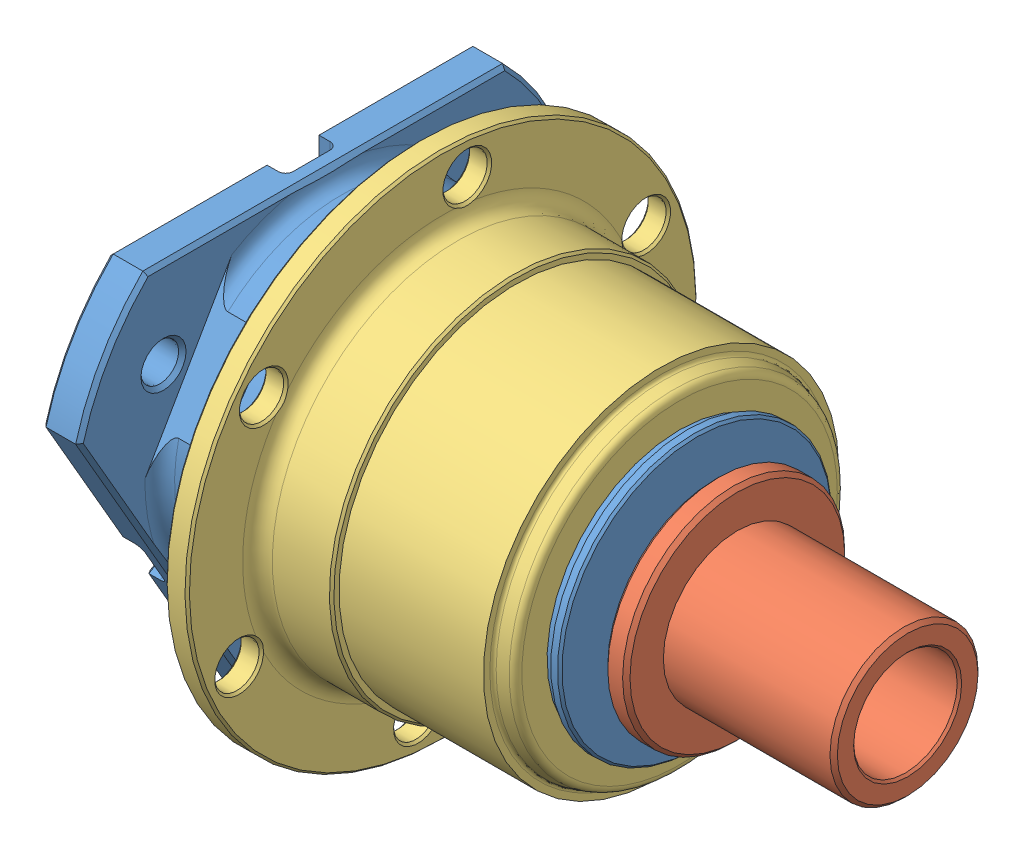
SolidWorks assembly F7_QUICK-RELEASE WITH CONNECTOR1, configuration Default. Lengths in mm.
Overall size (83.5 76.23 76.23).
3 component instances, 3 part files, 0 mates.
Components (placement in the parent):
- TE501054mozzoQR210-3d-1: TE501054mozzoQR210-3d [Default] at origin size (55 59 66.73)
- TE501053pernoQR210-3d-1: TE501053pernoQR210-3d [Default] at (83.5 0 0) x (-1 0 0) z (0 0 -1) size (65 30 30)
- TE501060boccolaQR200-3d-1: TE501060boccolaQR200-3d [Default] at (17.7 0 0) x (1 0 0) z (0 0.111007 0.99382) size (35 69 69)
